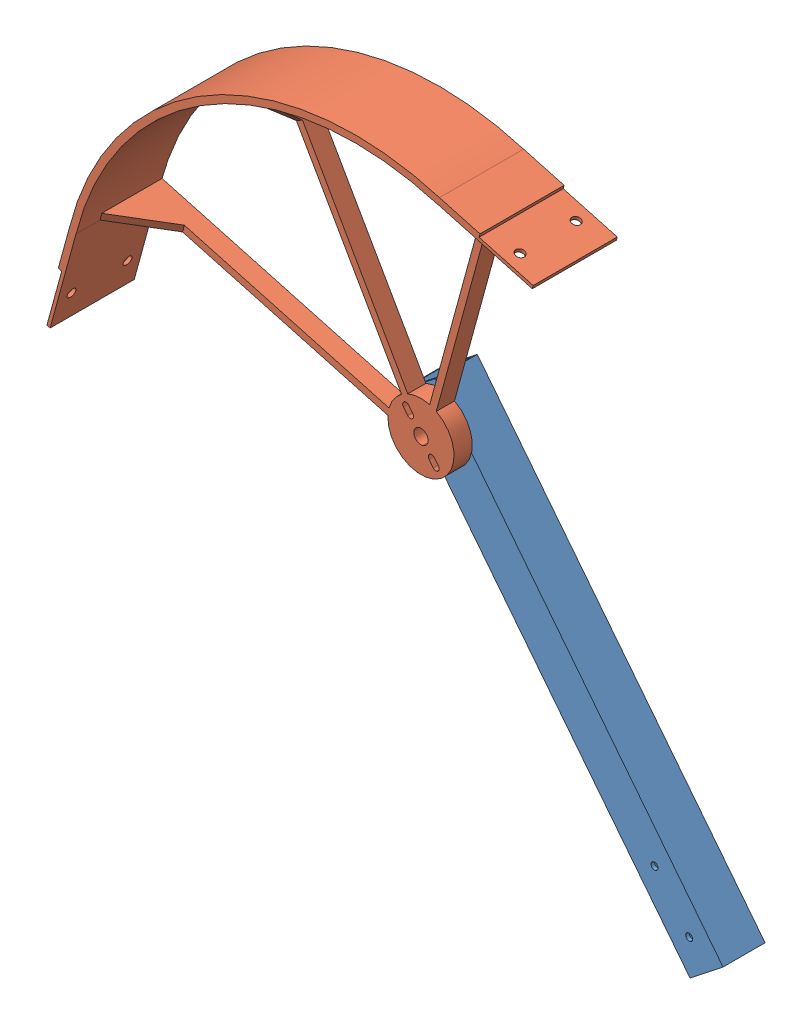
SolidWorks assembly Arm Assembly2, configuration Default. Lengths in mm.
Overall size (278.62 323.57 67.01).
4 component instances, 4 part files, 7 mates.
Components (placement in the parent):
- Arm-1: Arm [Default] at (163.5465 -14.9048 159.1998) size (145.36 177.44 19.05)
- Motor-1: Motor [Default] at (-40.9112 180.6853 186.5048) x (-0.99581 -0.091442 0) z (-0.091442 0.99581 0) size (254 42.2 254) (hidden)
- PropGuard2-1: PropGuard2 [Default] at (-40.2614 179.8597 178.2498) x (0.964585 -0.263772 0) z (-0.263772 -0.964585 0) size (180.97 38.1 180.97)
- spinningProp-1: spinningProp [Default] at (-40.9112 180.6853 221.0948) x (1 0 0) z (0 1 0) size (254 6.35 254) (hidden)
Mates (geometry in assembly coordinates):
- Tangent1: tangent aligned: plane of Arm-1 through (-57.0238 185.756 178.2498) normal (-0.61849 0.785792 0); cylinder of Motor-1 through (-40.9112 180.6853 212.2048) axis (0 0 -1) radius 13.95
- Coincident1: coincident anti-aligned: plane of Arm-1 through (163.5465 -14.9048 178.2498) normal (0 0 1); plane of PropGuard2-1 through (-40.2614 179.8597 178.2498) normal (0 0 -1)
- Concentric4: concentric anti-aligned: cylinder of Motor-1 through (-40.9112 180.6853 226.2048) axis (0 0 -1) radius 4; cylinder of spinningProp-1 through (-40.9112 180.6853 214.7448) axis (0 0 1) radius 3.175
- Distance1: distance = 2.54 mm anti-aligned: plane of Motor-1 through (-40.9112 180.6853 212.2048) normal (0 0 1); plane of spinningProp-1 through (-40.9112 180.6853 214.7448) normal (0 0 -1)
- Coincident3: coincident anti-aligned: plane of Motor-1 through (-40.9112 180.6853 186.5048) normal (0 0 -1); plane of PropGuard2-1 through (-40.2614 179.8597 186.5048) normal (0 0 1)
- Concentric5: concentric aligned: circle of Arm-1; circle of PropGuard2-1
- Parallel1: parallel aligned: line of Arm-1 through (-44.0307 187.0738 178.2498) axis (-0.61849 0.785792 0); line of PropGuard2-1 through (-43.9339 186.9896 178.2498) axis (-0.61849 0.785792 0)
